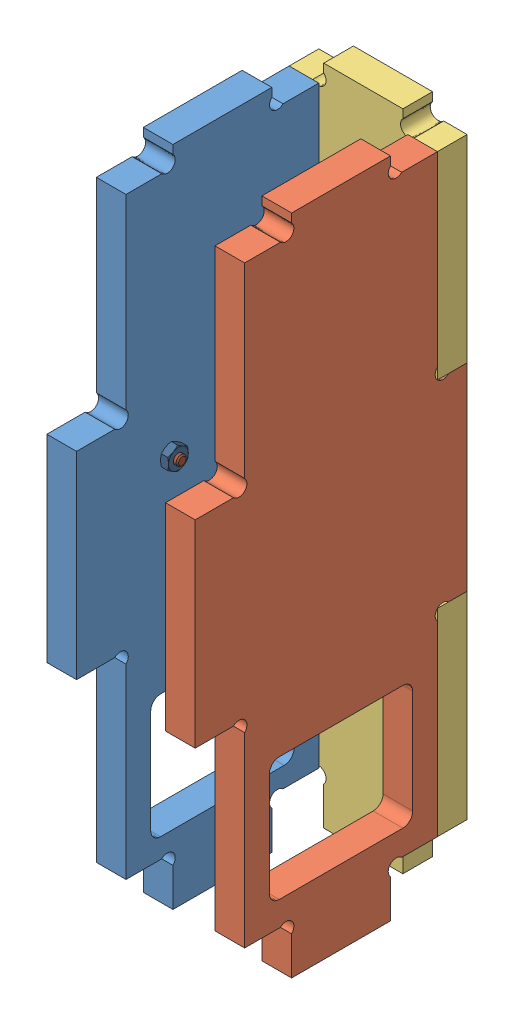
SolidWorks assembly pilier_gauche, configuration Défaut. Lengths in mm.
Overall size (44.26 134 55).
17 component instances, 11 part files, 26 mates.
Components (placement in the parent):
- pilier-cote-bouton-1: pilier-cote-bouton [Défaut] at (-45.8322 -68.3923 0) size (6 134 55)
- pilier-cote-2: pilier-cote [Défaut] at (-21.8322 -68.3923 0) size (6 134 55)
- pilier-devant-1: pilier-devant [Défaut] at (-45.8322 -68.3923 -55) size (30 134 6)
- vis-tf-m3x13-1: vis-tf-m3x13 [Défaut] at (-42.8322 41.6077 -55) x (-0.923728 -0.383049 0) z (0 0 -1) size (5.6 5.6 9)
- vis-tf-m3x13-2: vis-tf-m3x13 [Défaut] at (-18.8322 41.6077 -55) x (-0.923728 -0.383049 0) z (0 0 -1) size (5.6 5.6 9)
- entretoise-grove-1: entretoise-grove [Défaut] at (-47.8322 11.6077 -39) x (0 0 -1) z (1 0 0) size (4 4 2)
- entretoise-grove-2: entretoise-grove [Défaut] at (-47.8322 11.6077 -19) x (0 0 -1) z (1 0 0) size (4 4 2)
- Grove button-1: Grove button [Défaut] at (-46.5375 13.6873 -29) x (0 -1 0) z (0 0 -1) size (20 11.6 23.6)
  - PCB grove 20x20-1: PCB grove 20x20 [Défaut] at (2.0795 1.2947 0) size (20 1.6 23.6)
  - 603 resistor 102-1: 603 resistor 102 [Default] at (2.0895 2.8947 -6.319) x (0 0 1) z (-1 0 0) size (2.36 0.62 1.03)
  - tactileswitch-CMS-1: tactileswitch-CMS [Default] at (-2.4169 2.8947 0.0035) x (0 0 1) z (-1 0 0) size (8.41 4.95 6.01)
  - Connecteur Grove (droit CMS)-1: Connecteur Grove (droit CMS) [Défaut] at (5.0795 2.8947 0) x (-1 0 0) z (0 1 0) size (6.5 14 10)
  - 603 resistor 102-2: 603 resistor 102 [Default] at (3.5895 2.8947 -6.319) x (0 0 1) z (-1 0 0) size (2.36 0.62 1.03)
- ecrou-h-1: ecrou-h [6007 HU M2] at (-38.2322 11.6077 -39) x (0 -0.866025 0.5) z (0 0.5 0.866025) size (4 1.6 4.62)
- ecrou-h-2: ecrou-h [6007 HU M2] at (-38.2322 11.6077 -19) x (0 -0.866025 0.5) z (0 0.5 0.866025) size (4 1.6 4.62)
- vis-chc-1: vis-chc [Vis CHC M2x12] at (-49.4322 11.6077 -19) x (0 0.931711 0.363201) z (0 -0.363201 0.931711) size (3.8 14 3.8)
- vis-chc-2: vis-chc [Vis CHC M2x12] at (-49.4322 11.6077 -39) x (0 0.992378 -0.123233) z (0 0.123233 0.992378) size (3.8 14 3.8)
Mates (geometry in assembly coordinates):
- Coïncidente1: coincident aligned: plane of pilier-cote-bouton-1 through (-39.8322 61.6077 -41.7627) normal (0 1 0); plane of pilier-devant-1 through (-41.0949 61.6077 -49) normal (0 1 0)
- Coïncidente2: coincident aligned: plane of pilier-cote-2 through (-15.8322 61.6077 -41.7627) normal (0 1 0); plane of pilier-devant-1 through (-20.5694 61.6077 -49) normal (0 1 0)
- Coïncidente3: coincident aligned: plane of pilier-cote-bouton-1 through (-45.8322 -19.5236 -50.1314) normal (-1 0 0); plane of pilier-devant-1 through (-45.8322 21.6077 -49) normal (-1 0 0)
- Coïncidente4: coincident aligned: plane of pilier-cote-bouton-1 through (-39.8322 21.6077 -55) normal (0 0 -1); plane of pilier-devant-1 through (-21.7008 -59.5236 -55) normal (0 0 -1)
- Coïncidente5: coincident aligned: plane of pilier-cote-2 through (-15.8322 21.6077 -55) normal (0 0 -1); plane of pilier-devant-1 through (-21.7008 -59.5236 -55) normal (0 0 -1)
- Coïncidente6: coincident aligned: plane of pilier-cote-2 through (-15.8322 -19.5236 -50.1314) normal (1 0 0); plane of pilier-devant-1 through (-15.8322 21.6077 -49) normal (1 0 0)
- Coïncidente7: coincident aligned: line of pilier-devant-1 through (-42.8322 41.6077 -49) axis (0 0 -1); line of VIS TF 3 X 13-1 through (-42.8322 41.6077 -48.5115) axis (0 0 -1)
- Coïncidente8: coincident aligned: plane of pilier-devant-1 through (-21.7008 -59.5236 -55) normal (0 0 -1); circle of VIS TF 3 X 13-1
- Coïncidente10: coincident aligned: line of pilier-devant-1 through (-18.8322 41.6077 -49) axis (0 0 -1); line of VIS TF 3 X 13-2 through (-18.8322 41.6077 -48.5115) axis (0 0 -1)
- Coïncidente11: coincident aligned: plane of pilier-devant-1 through (-21.7008 -59.5236 -55) normal (0 0 -1); circle of VIS TF 3 X 13-2
- Coaxiale1: concentric anti-aligned: cylinder of Grove button-1/PCB grove 20x20-1 through (-49.4322 11.6077 -39) axis (1 0 0) radius 1.1; cylinder of entretoise-grove-1 through (-45.8322 11.6077 -39) axis (-1 0 0) radius 1
- Coïncidente14: coincident anti-aligned: plane of Grove button-1/PCB grove 20x20-1 through (-47.8322 11.6077 -29) normal (1 0 0); plane of entretoise-grove-1 through (-47.8322 11.6077 -39) normal (-1 0 0)
- Coaxiale2: concentric anti-aligned: cylinder of Grove button-1/PCB grove 20x20-1 through (-49.4322 11.6077 -19) axis (1 0 0) radius 1.1; cylinder of entretoise-grove-2 through (-45.8322 11.6077 -19) axis (-1 0 0) radius 1
- Coïncidente15: coincident anti-aligned: plane of Grove button-1/PCB grove 20x20-1 through (-47.8322 11.6077 -29) normal (1 0 0); plane of entretoise-grove-2 through (-47.8322 11.6077 -19) normal (-1 0 0)
- Coïncidente16: coincident anti-aligned: plane of pilier-cote-bouton-1 through (-45.8322 -19.5236 -50.1314) normal (-1 0 0); plane of entretoise-grove-2 through (-45.8322 11.6077 -19) normal (1 0 0)
- Coaxiale3: concentric aligned: cylinder of pilier-cote-bouton-1 through (-39.8322 11.6077 -39) axis (-1 0 0) radius 1; cylinder of entretoise-grove-1 through (-45.8322 11.6077 -39) axis (-1 0 0) radius 1
- Coaxiale4: concentric aligned: cylinder of pilier-cote-bouton-1 through (-39.8322 11.6077 -19) axis (-1 0 0) radius 1; cylinder of entretoise-grove-2 through (-45.8322 11.6077 -19) axis (-1 0 0) radius 1
- Coaxiale5: concentric anti-aligned: cylinder of Grove button-1/PCB grove 20x20-1 through (-49.4322 11.6077 -39) axis (1 0 0) radius 1.1; cylinder of vis-chc-2 through (-37.4322 11.6077 -39) axis (-1 0 0) radius 1
- Coaxiale6: concentric anti-aligned: line of Grove button-1/PCB grove 20x20-1 through (-49.4322 11.6077 -19) axis (1 0 0); cylinder of vis-chc-1 through (-37.4322 11.6077 -19) axis (-1 0 0) radius 1
- Coïncidente19: coincident anti-aligned: plane of Grove button-1/PCB grove 20x20-1 through (-49.4322 11.6077 -29) normal (-1 0 0); plane of vis-chc-1 through (-49.4322 11.6077 -19) normal (1 0 0)
- Coaxiale7: concentric anti-aligned: cylinder of ecrou-h-1 through (-39.8322 11.6077 -39) axis (1 0 0) radius 0.7835; cylinder of vis-chc-2 through (-37.4322 11.6077 -39) axis (-1 0 0) radius 1
- Coïncidente20: coincident anti-aligned: plane of pilier-cote-bouton-1 through (-39.8322 -19.5236 -50.1314) normal (1 0 0); plane of ecrou-h-1 through (-39.8322 9.2983 -39) normal (-1 0 0)
- Parallèle2: parallel anti-aligned: plane of pilier-devant-1 through (-21.7008 -59.5236 -49) normal (0 0 1); plane of ecrou-h-1 through (-39.8322 10.453 -41) normal (0 0 -1)
- Coaxiale8: concentric anti-aligned: cylinder of ecrou-h-2 through (-39.8322 11.6077 -19) axis (1 0 0) radius 0.7835; cylinder of vis-chc-1 through (-37.4322 11.6077 -19) axis (-1 0 0) radius 1
- Coïncidente22: coincident anti-aligned: plane of pilier-cote-bouton-1 through (-39.8322 -19.5236 -50.1314) normal (1 0 0); plane of ecrou-h-2 through (-39.8322 9.2983 -19) normal (-1 0 0)
- Parallèle3: parallel anti-aligned: plane of pilier-devant-1 through (-21.7008 -59.5236 -49) normal (0 0 1); plane of ecrou-h-2 through (-39.8322 10.453 -21) normal (0 0 -1)
